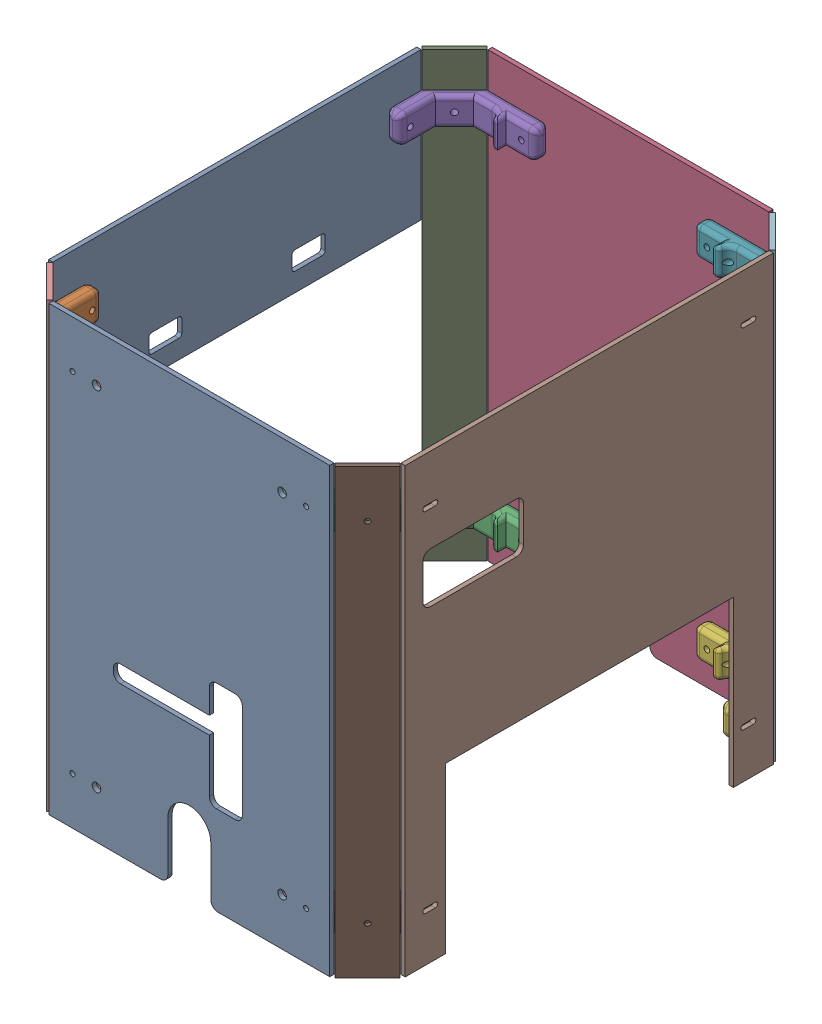
SolidWorks assembly Assemblage_plexi_1, configuration Défaut. Lengths in mm.
Overall size (248.9 309 309.4).
16 component instances, 6 part files, 40 mates.
Components (placement in the parent):
- Plexi_V1-1: Plexi_V1 [Défaut] at (-15.4571 -10.0262 -1.5) size (196 309 3)
- Support_Plexi-1: Support_Plexi [Défaut] at (-80.2071 111.4738 -11.5) size (66.7 20 48.2)
- Support_Plexi-3: Support_Plexi [Défaut] at (49.2929 111.4738 -11.5) x (-1 0 0) z (0 0 1) size (66.7 20 48.2)
- Support_Plexi-4: Support_Plexi [Défaut] at (49.2929 -131.5262 -11.5) x (-1 0 0) z (0 0 1) size (66.7 20 48.2)
- Support_Plexi-5: Support_Plexi [Défaut] at (-80.2071 111.4738 -294.9) x (1 0 0) z (0 0 -1) size (66.7 20 48.2)
- Support_Plexi-6: Support_Plexi [Défaut] at (49.2929 -131.5262 -294.9) x (-1 0 0) z (0 0 -1) size (66.7 20 48.2)
- Support_Plexi-7: Support_Plexi [Défaut] at (49.2929 111.4738 -294.9) x (-1 0 0) z (0 0 -1) size (66.7 20 48.2)
- Plexi_Arriere_V2-1: Plexi_Arriere_V2 [Défaut] at (105.9929 -10.0262 -153.2) x (0 0 -1) z (1 0 0) size (257 309 3)
- Plexi_Angle-1: Plexi_Angle [Défaut] at (-127.4284 -10.0262 -295.4213) x (0.707107 0 -0.707107) z (0.707107 0 0.707107) size (32 309 3)
- Plexi_Angle-2: Plexi_Angle [Défaut] at (-127.4284 -10.0262 -10.9787) x (-0.707107 0 -0.707107) z (0.707107 0 -0.707107) size (32 309 3)
- Plexi_Angle-3: Plexi_Angle [Défaut] at (96.5142 -10.0262 -10.9787) x (-0.707107 0 0.707107) z (-0.707107 0 -0.707107) size (32 309 3)
- Plexi_Angle-4: Plexi_Angle [Défaut] at (96.5142 -10.0262 -295.4213) x (0.707107 0 0.707107) z (-0.707107 0 0.707107) size (32 309 3)
- Plexi_Avant-1: Plexi_Avant [Défaut] at (-139.9071 92.9738 -153.2) x (0 0 -1) z (1 0 0) size (257 103 3)
- Support_Plexi_2-1: Support_Plexi_2 [Défaut] at (-80.2071 -131.5262 -11.5) size (61.67 20 21)
- Support_Plexi_2-2: Support_Plexi_2 [Défaut] at (-80.2071 -131.5262 -294.9) x (1 0 0) z (0 0 -1) size (61.67 20 21)
- Plexi_V1-3: Plexi_V1 [Défaut] at (-15.4571 -10.0262 -307.9) x (1 0 0) z (0 0 1) size (196 309 3)
Mates (geometry in assembly coordinates):
- Coaxiale1: concentric anti-aligned: cylinder of Plexi_V1-1 through (-96.9571 111.4738 1.5) axis (0 0 -1) radius 1.75; cylinder of Support_Plexi-1 through (-96.9571 111.4738 -49.701) axis (0 0 1) radius 2
- Coïncidente1: coincident anti-aligned: plane of Plexi_V1-1 through (-15.4571 -10.0262 -1.5) normal (0 0 -1); plane of Support_Plexi-1 through (-80.2071 111.4738 -1.5) normal (0 0 1)
- Parallèle1: parallel aligned: plane of Plexi_V1-1 through (82.5429 144.4738 1.5) normal (0 1 0); plane of Support_Plexi-1 through (-70.2071 121.4738 -8.5) normal (0 1 0)
- Coaxiale2: concentric anti-aligned: line of Plexi_V1-1 through (66.0429 111.4738 1.5) axis (0 0 -1); axis of Support_Plexi-3 through (66.0429 111.4738 -15.5) axis (0 0 1)
- Coïncidente3: coincident anti-aligned: plane of Plexi_V1-1 through (-15.4571 -10.0262 -1.5) normal (0 0 -1); plane of Support_Plexi-3 through (49.2929 111.4738 -1.5) normal (0 0 1)
- Coïncidente4: coincident aligned: plane of Support_Plexi-1 through (-70.2071 121.4738 -8.5) normal (0 1 0); plane of Support_Plexi-3 through (39.2929 121.4738 -8.5) normal (0 1 0)
- Coïncidente7: coincident anti-aligned: plane of Plexi_V1-1 through (-15.4571 -10.0262 -1.5) normal (0 0 -1); plane of Support_Plexi-4 through (49.2929 -131.5262 -1.5) normal (0 0 1)
- Coaxiale4: concentric anti-aligned: cylinder of Plexi_V1-1 through (66.0429 -131.5262 1.5) axis (0 0 -1) radius 1.75; cylinder of Support_Plexi-4 through (66.0429 -131.5262 -49.701) axis (0 0 1) radius 2
- Coïncidente12: coincident aligned: plane of Support_Plexi-5 through (-70.2071 121.4738 -297.9) normal (0 1 0); plane of Support_Plexi-7 through (39.2929 121.4738 -297.9) normal (0 1 0)
- Coaxiale9: concentric anti-aligned: cylinder of Support_Plexi-7 through (39.2919 111.4738 -264.2) axis (1 0 0) radius 2; cylinder of Plexi_V1_Arriere-1 through (108.9929 111.4738 -264.2) axis (-1 0 0) radius 1.75
- Coaxiale10: concentric anti-aligned: cylinder of Support_Plexi-3 through (39.2919 111.4738 -42.2) axis (1 0 0) radius 2; cylinder of Plexi_V1_Arriere-1 through (108.9929 111.4738 -42.2) axis (-1 0 0) radius 1.75
- Coïncidente18: coincident anti-aligned: plane of Support_Plexi-3 through (105.9929 121.4738 -49.7) normal (1 0 0); plane of Plexi_V1_Arriere-1 through (105.9929 -10.0262 -153.2) normal (-1 0 0)
- Coïncidente20: coincident anti-aligned: plane of Support_Plexi-7 through (82.7929 101.4738 -304.9) normal (0.707107 0 -0.707107); plane of Plexi_Angle-4 through (94.3929 -10.0262 -293.3) normal (-0.707107 0 0.707107)
- Coïncidente21: coincident anti-aligned: plane of Support_Plexi-3 through (82.7929 121.4738 -1.5) normal (0.707107 0 0.707107); plane of Plexi_Angle-3 through (94.3929 -10.0262 -13.1) normal (-0.707107 0 -0.707107)
- Coïncidente22: coincident anti-aligned: plane of Support_Plexi-1 through (-113.7071 101.4738 -1.5) normal (-0.707107 0 0.707107); plane of Plexi_Angle-2 through (-125.3071 -10.0262 -13.1) normal (0.707107 0 -0.707107)
- Coïncidente23: coincident anti-aligned: plane of Support_Plexi-5 through (-113.7071 121.4738 -304.9) normal (-0.707107 0 -0.707107); plane of Plexi_Angle-1 through (-125.3071 -10.0262 -293.3) normal (0.707107 0 0.707107)
- Coaxiale13: concentric aligned: cylinder of Support_Plexi-5 through (-79.4561 111.4738 -247.449) axis (-0.707107 0 -0.707107) radius 2; cylinder of Plexi_Angle-1 through (-125.3071 111.4738 -293.3) axis (-0.707107 0 -0.707107) radius 1.75
- Coaxiale15: concentric aligned: cylinder of Support_Plexi-1 through (-79.4561 111.4738 -58.951) axis (-0.707107 0 0.707107) radius 2; cylinder of Plexi_Angle-2 through (-125.3071 111.4738 -13.1) axis (-0.707107 0 0.707107) radius 1.75
- Coaxiale17: concentric aligned: cylinder of Support_Plexi-4 through (48.5419 -131.5262 -58.951) axis (0.707107 0 0.707107) radius 2; cylinder of Plexi_Angle-3 through (94.3929 -131.5262 -13.1) axis (0.707107 0 0.707107) radius 1.75
- Coaxiale18: concentric aligned: cylinder of Support_Plexi-3 through (48.5419 111.4738 -58.951) axis (0.707107 0 0.707107) radius 2; cylinder of Plexi_Angle-3 through (94.3929 111.4738 -13.1) axis (0.707107 0 0.707107) radius 1.75
- Coaxiale19: concentric aligned: cylinder of Support_Plexi-6 through (48.5419 -131.5262 -247.449) axis (0.707107 0 -0.707107) radius 2; cylinder of Plexi_Angle-4 through (94.3929 -131.5262 -293.3) axis (0.707107 0 -0.707107) radius 1.75
- Coaxiale20: concentric aligned: cylinder of Support_Plexi-7 through (48.5419 111.4738 -247.449) axis (0.707107 0 -0.707107) radius 2; cylinder of Plexi_Angle-4 through (94.3929 111.4738 -293.3) axis (0.707107 0 -0.707107) radius 1.75
- Coaxiale21: concentric aligned: cylinder of Support_Plexi-5 through (-70.2061 111.4738 -264.2) axis (-1 0 0) radius 2; cylinder of Plexi_Avant-1 through (-136.9071 111.4738 -264.2) axis (-1 0 0) radius 1.75
- Coaxiale22: concentric aligned: cylinder of Support_Plexi-1 through (-70.2061 111.4738 -42.2) axis (-1 0 0) radius 2; cylinder of Plexi_Avant-1 through (-136.9071 111.4738 -42.2) axis (-1 0 0) radius 1.75
- Coïncidente24: coincident anti-aligned: plane of Support_Plexi-1 through (-136.9071 101.4738 -49.7) normal (-1 0 0); plane of Plexi_Avant-1 through (-136.9071 92.9738 -153.2) normal (1 0 0)
- Coaxiale23: concentric anti-aligned: cylinder of Plexi_V1-1 through (-96.9571 -131.5262 1.5) axis (0 0 -1) radius 1.75; cylinder of Support_Plexi_2-1 through (-96.9571 -131.5262 -49.701) axis (0 0 1) radius 2
- Coaxiale24: concentric aligned: cylinder of Plexi_V1-1 through (-80.2071 -131.5262 1.5) axis (0 0 -1) radius 3; cylinder of Support_Plexi_2-1 through (-80.2071 -131.5262 -1.5) axis (0 0 -1) radius 3
- Coaxiale25: concentric aligned: cylinder of Plexi_Angle-2 through (-125.3071 -131.5262 -13.1) axis (-0.707107 0 0.707107) radius 1.75; cylinder of Support_Plexi_2-1 through (-79.4561 -131.5262 -58.951) axis (-0.707107 0 0.707107) radius 2
- Coaxiale28: concentric aligned: cylinder of Plexi_Angle-1 through (-125.3071 -131.5262 -293.3) axis (-0.707107 0 -0.707107) radius 1.75; cylinder of Support_Plexi_2-2 through (-79.4561 -131.5262 -247.449) axis (-0.707107 0 -0.707107) radius 2
- Coaxiale29: concentric anti-aligned: cylinder of Support_Plexi-6 through (39.2919 -131.5262 -264.2) axis (1 0 0) radius 2; cylinder of Plexi_V1_Arriere-1 through (108.9929 -131.5262 -264.2) axis (-1 0 0) radius 1.75
- Coaxiale30: concentric anti-aligned: cylinder of Support_Plexi-4 through (39.2919 -131.5262 -42.2) axis (1 0 0) radius 2; cylinder of Plexi_V1_Arriere-1 through (108.9929 -131.5262 -42.2) axis (-1 0 0) radius 1.75
- Coaxiale31: concentric aligned: cylinder of Support_Plexi-6 through (48.5419 -131.5262 -247.449) axis (0.707107 0 -0.707107) radius 2; cylinder of Plexi_Angle-4 through (94.3929 -131.5262 -293.3) axis (0.707107 0 -0.707107) radius 1.75
- Coïncidente25: coincident anti-aligned: plane of Support_Plexi-6 through (82.7929 -141.5262 -304.9) normal (0.707107 0 -0.707107); plane of Plexi_Angle-4 through (94.3929 -10.0262 -293.3) normal (-0.707107 0 0.707107)
- Coïncidente26: coincident anti-aligned: plane of Support_Plexi-6 through (105.9929 -141.5262 -256.7) normal (1 0 0); plane of Plexi_V1_Arriere-1 through (105.9929 -10.0262 -153.2) normal (-1 0 0)
- Coaxiale32: concentric aligned: cylinder of Support_Plexi-7 through (66.0429 111.4738 -256.699) axis (0 0 -1) radius 2; cylinder of Plexi_V1-3 through (66.0429 111.4738 -304.9) axis (0 0 -1) radius 1.75
- Coaxiale33: concentric anti-aligned: cylinder of Support_Plexi-7 through (49.2929 111.4738 -304.9) axis (0 0 1) radius 3; cylinder of Plexi_V1-3 through (49.2929 111.4738 -304.9) axis (0 0 -1) radius 3
- Coïncidente27: coincident anti-aligned: plane of Support_Plexi-7 through (49.2929 111.4738 -304.9) normal (0 0 -1); plane of Plexi_V1-3 through (-15.4571 -10.0262 -304.9) normal (0 0 1)
- Coaxiale34: concentric anti-aligned: cylinder of Support_Plexi-5 through (-80.2071 111.4738 -304.9) axis (0 0 1) radius 3; cylinder of Plexi_V1-3 through (-80.2071 111.4738 -304.9) axis (0 0 -1) radius 3
- Coaxiale35: concentric aligned: cylinder of Support_Plexi-5 through (-96.9571 111.4738 -256.699) axis (0 0 -1) radius 2; cylinder of Plexi_V1-3 through (-96.9571 111.4738 -304.9) axis (0 0 -1) radius 1.75
- Coaxiale36: concentric aligned: cylinder of Support_Plexi_2-2 through (-96.9571 -131.5262 -256.699) axis (0 0 -1) radius 2; cylinder of Plexi_V1-3 through (-96.9571 -131.5262 -304.9) axis (0 0 -1) radius 1.75
